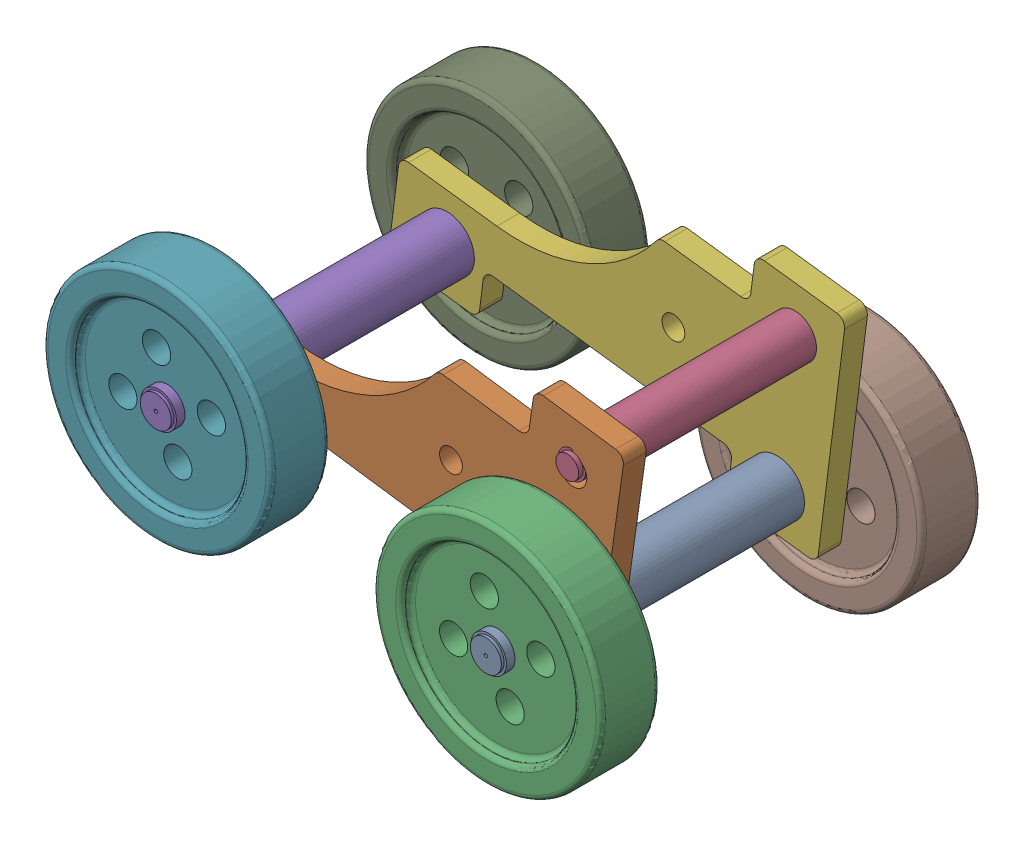
SolidWorks assembly assemble 7-8-23, configuration Default. Lengths in mm.
Overall size (1398.08 834.11 840).
9 component instances, 4 part files, 16 mates.
Components (placement in the parent):
- part 1 2-8-23-1: part 1 2-8-23 [Default] at (-748.2062 2160.7935 435.1425) size (120 120 840)
- part 3 2-8-23-1: part 3 2-8-23 [Default] at (-663.1017 2047.8456 900.1425) x (-0.990262 0.139217 0) z (0 0 -1) size (950 500 50)
- part 4 2-8--23-1: part 4 2-8--23 [Default] at (-748.2062 2160.7935 942.6425) x (0.958842 0.283939 0) z (0 0 1) size (500 500 130)
- Part2 2-8-23-1: Part2 2-8-23 [Default] at (-709.2821 2468.7168 435.1425) size (95 95 560)
- part 1 2-8-23-5: part 1 2-8-23 [Default] at (-1473.4067 2262.7464 435.1425) x (0.999786 0.02071 0) z (0 0 1) size (120 120 840)
- part 3 2-8-23-20: part 3 2-8-23 [Default] at (-660.1389 2059.3454 410.1425) x (-0.992135 0.125175 0) z (0 0 -1) size (950 500 50)
- part 4 2-8--23-2: part 4 2-8--23 [Default] at (-1473.4067 2262.7464 942.6425) x (0.972266 0.233876 0) z (0 0 1) size (500 500 130)
- part 4 2-8--23-3: part 4 2-8--23 [Default] at (-748.2062 2160.7935 237.6425) x (-0.337272 -0.941407 0) z (0 0 1) size (500 500 130)
- part 4 2-8--23-4: part 4 2-8--23 [Default] at (-1473.4067 2262.7464 237.6425) x (0.675211 0.737625 0) z (0 0 1) size (500 500 130)
Mates (geometry in assembly coordinates):
- Concentric8: concentric aligned: cylinder of part 3 2-8-23-1 through (-1473.4067 2262.7464 925.1425) axis (0 0 -1) radius 40; cylinder of part 1 2-8-23-5 through (-1473.4067 2262.7464 875.1425) axis (0 0 -1) radius 60
- Coincident8: coincident anti-aligned: plane of part 3 2-8-23-1 through (-1309.8658 2724.4751 875.1425) normal (0 0 -1); plane of part 1 2-8-23-5 through (-1473.4067 2262.7464 875.1425) normal (0 0 1)
- Concentric9: concentric anti-aligned: cylinder of part 1 2-8-23-5 through (-1473.4067 2262.7464 345.1425) axis (0 0 1) radius 41; cylinder of part 3 2-8-23-20 through (-1473.4067 2262.7464 435.1425) axis (0 0 -1) radius 40
- Coincident9: coincident aligned: circle of part 1 2-8-23-5; plane of part 3 2-8-23-20 through (-1316.4227 2726.7454 435.1425) normal (0 0 1)
- Concentric10: concentric aligned: cylinder of part 1 2-8-23-1 through (-748.2062 2160.7935 875.1425) axis (0 0 -1) radius 60; circle of part 3 2-8-23-1
- Coincident10: coincident anti-aligned: plane of part 1 2-8-23-1 through (-748.2062 2160.7935 435.1425) normal (0 0 -1); plane of part 3 2-8-23-20 through (-1316.4227 2726.7454 435.1425) normal (0 0 1)
- Concentric11: concentric anti-aligned: cylinder of part 1 2-8-23-1 through (-748.2062 2160.7935 1068.8925) axis (0 0 -1) radius 39; cylinder of part 4 2-8--23-1 through (-748.2062 2160.7935 942.6425) axis (0 0 1) radius 39
- Concentric12: concentric anti-aligned: cylinder of part 1 2-8-23-5 through (-1473.4067 2262.7464 1068.8925) axis (0 0 -1) radius 39; cylinder of part 4 2-8--23-2 through (-1473.4067 2262.7464 942.6425) axis (0 0 1) radius 39
- Coincident11: coincident anti-aligned: circle of part 1 2-8-23-5; plane of part 4 2-8--23-2 through (-1473.4067 2262.7464 965.1425) normal (0 0 -1)
- Coincident12: coincident anti-aligned: circle of part 1 2-8-23-1; plane of part 4 2-8--23-1 through (-748.2062 2160.7935 965.1425) normal (0 0 -1)
- Concentric13: concentric anti-aligned: circle of part 1 2-8-23-1; cylinder of part 4 2-8--23-3 through (-748.2062 2160.7935 237.6425) axis (0 0 1) radius 39
- Coincident13: coincident anti-aligned: circle of part 1 2-8-23-1; plane of part 4 2-8--23-3 through (-748.2062 2160.7935 345.1425) normal (0 0 1)
- Concentric14: concentric aligned: cylinder of part 1 2-8-23-5 through (-1473.4067 2262.7464 241.3925) axis (0 0 1) radius 39; cylinder of part 4 2-8--23-4 through (-1473.4067 2262.7464 237.6425) axis (0 0 1) radius 39
- Coincident14: coincident anti-aligned: circle of part 1 2-8-23-5; plane of part 4 2-8--23-4 through (-1473.4067 2262.7464 345.1425) normal (0 0 1)
- Concentric15: concentric aligned: cylinder of Part2 2-8-23-1 through (-709.2821 2468.7168 875.1425) axis (0 0 -1) radius 47.5; circle of part 3 2-8-23-20
- Coincident15: coincident anti-aligned: plane of part 3 2-8-23-1 through (-1309.8658 2724.4751 875.1425) normal (0 0 -1); plane of Part2 2-8-23-1 through (-709.2821 2468.7168 875.1425) normal (0 0 1)
